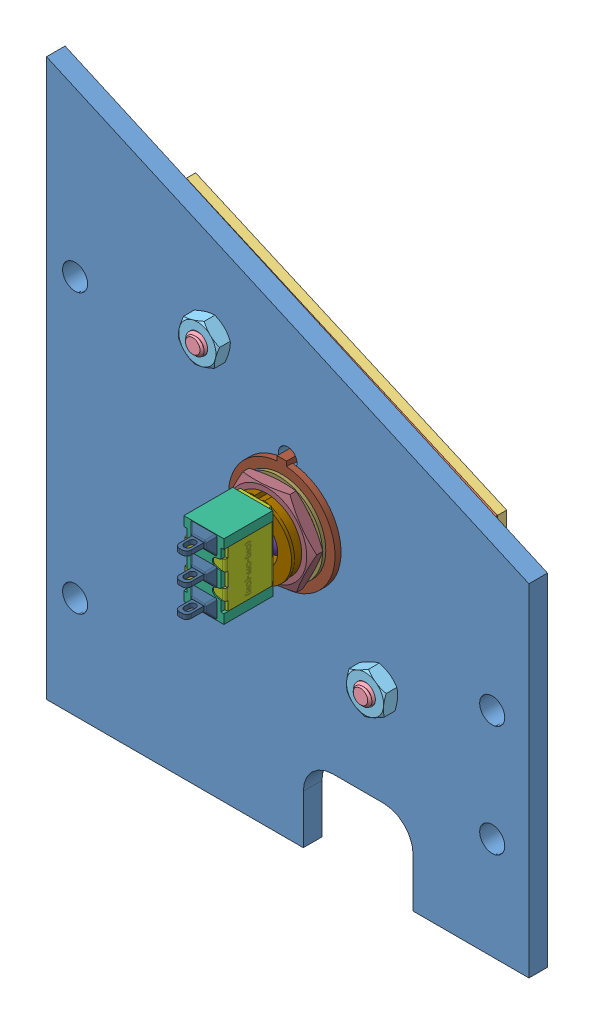
SolidWorks assembly FIRE TEST Panel, configuration Default. Lengths in mm.
Overall size (82.55 80.05 42.41).
17 component instances, 13 part files, 11 mates.
Components (placement in the parent):
- FIRE TEST Panel Backplate-1: FIRE TEST Panel Backplate [Default] at origin size (82.55 80.05 3.17)
- FIRE TEST Panel Lightplate-1: FIRE TEST Panel Lightplate [Default] at (0 0 -3.175) x (-1 0 0) z (0 0 -1) size (55.25 58.42 4.76)
- FIRE TEST Panel Legend Plate-1: FIRE TEST Panel Legend Plate [Default] at (0 0 -7.9375) x (-1 0 0) z (0 0 -1) size (55.25 58.42 1.59)
- 91249A148 - PHS, 6-32 X .500, 18-8, BLACK-OXIDE-1: 91249A148 - PHS, 6-32 X .500, 18-8, BLACK-OXIDE [91249A148] at (28.194 68.072 3.175) x (-0.99905 0.043571 0) z (0 0 -1) size (6.86 6.86 15.21)
- 90760A007 - NUT, 6-32, JAM, STEEL, ZINC-PLATED-1: 90760A007 - NUT, 6-32, JAM, STEEL, ZINC-PLATED [90760A007] at (28.194 68.072 1.1906) x (0.275217 -0.961382 0) z (-0.961382 -0.275217 0) size (6.35 2.99 7.33)
- 91249A148 - PHS, 6-32 X .500, 18-8, BLACK-OXIDE-2: 91249A148 - PHS, 6-32 X .500, 18-8, BLACK-OXIDE [91249A148] at (56.896 30.48 3.175) x (-0.993321 -0.115383 0) z (0 0 -1) size (6.86 6.86 15.21)
- 90760A007 - NUT, 6-32, JAM, STEEL, ZINC-PLATED-2: 90760A007 - NUT, 6-32, JAM, STEEL, ZINC-PLATED [90760A007] at (56.896 30.48 1.1906) x (0.424166 -0.905585 0) z (-0.905585 -0.424166 0) size (6.35 2.99 7.33)
- 100SPxT8B13M1QEH - SWITCH, TOGGLE, SPDT, 18mm BAT-1: 100SPxT8B13M1QEH - SWITCH, TOGGLE, SPDT, 18mm BAT [100SP4T8B13M1QEH] at (41.275 46.99 14.3538) x (0 1 0) z (0 0 -1) size (19 18.28 42.41)
  - 100-300SPXBODY-1: 100-300SPXBODY [Default] at origin size (12.7 6.86 8.38)
  - 100SPXBRACKET_1-1: 100SPXBRACKET_1 [100SP4T8B13M1QEH] at (0 0 0.19) size (12.7 6.86 8.7)
  - 100T8-1: 100T8 [Default] at (0 0 13.35) x (-0.976296 0 -0.21644) z (-0.21644 0 0.976296) size (7.5 7.5 28.63)
  - 100B13BUSHING-1: 100B13BUSHING [Default] at (0 0 0.51) x (-1 0 0) z (0 0 1) size (12.18 12.24 11.89)
  - 100-300SPXM1-1: 100-300SPXM1 [Default] x (-1 0 0) z (0 0 -1) size (12.56 4.43 3.96)
  - HDW17 - LOCKING RING, B13-1: HDW17 - LOCKING RING, B13 [Default] at (0 0 13.3378) x (0 1 0) z (1 0 0) size (18.24 3.3 19)
  - HDW12 - LOCK WASHER, B13-1: HDW12 - LOCK WASHER, B13 [Default] at (0 0 12.779) x (1 0 0) z (0 -1 0) size (15.06 0.56 15.06)
  - HDW4 - NUT, B13-1: HDW4 - NUT, B13 [Default] at (0 0 10.7978) x (0.996778 -0.080205 0) z (-0.080205 -0.996778 0) size (14 1.98 16.16)
  - HDW4 - NUT, B13-2: HDW4 - NUT, B13 [Default] at (0 0 17.5288) x (0.98588 -0.167452 0) z (-0.167452 -0.98588 0) size (14 1.98 16.16)
Mates (geometry in assembly coordinates):
- Concentric1: concentric anti-aligned: cylinder of FIRE TEST Panel Legend Plate-1 through (28.194 68.072 -9.525) axis (0 0 -1) radius 2.1526; cylinder of 91249A148 - PHS, 6-32 X .500, 18-8, BLACK-OXIDE-1 through (28.194 68.072 3.175) axis (0 0 1) radius 3.429
- Concentric2: concentric aligned: cylinder of 91249A148 - PHS, 6-32 X .500, 18-8, BLACK-OXIDE-1 through (28.194 68.072 3.175) axis (0 0 1) radius 3.429; circle of 90760A007 - NUT, 6-32, JAM, STEEL, ZINC-PLATED-1
- Coincident1: coincident anti-aligned: plane of FIRE TEST Panel Backplate-1 through (49.022 8.382 0) normal (0 0 1); plane of 90760A007 - NUT, 6-32, JAM, STEEL, ZINC-PLATED-1 through (29.0825 71.6289 0) normal (0 0 -1)
- Coincident2: coincident anti-aligned: plane of FIRE TEST Panel Legend Plate-1 through (9.652 65.0875 -9.525) normal (0 0 -1); plane of 91249A148 - PHS, 6-32 X .500, 18-8, BLACK-OXIDE-1 through (28.194 68.072 -9.525) normal (0 0 1)
- Concentric3: concentric aligned: cylinder of 91249A148 - PHS, 6-32 X .500, 18-8, BLACK-OXIDE-2 through (56.896 30.48 3.175) axis (0 0 1) radius 3.429; circle of 90760A007 - NUT, 6-32, JAM, STEEL, ZINC-PLATED-2
- Coincident3: coincident anti-aligned: plane of FIRE TEST Panel Backplate-1 through (49.022 8.382 0) normal (0 0 1); plane of 90760A007 - NUT, 6-32, JAM, STEEL, ZINC-PLATED-2 through (57.2093 34.1328 0) normal (0 0 -1)
- Coincident4: coincident anti-aligned: plane of FIRE TEST Panel Legend Plate-1 through (9.652 65.0875 -9.525) normal (0 0 -1); plane of 91249A148 - PHS, 6-32 X .500, 18-8, BLACK-OXIDE-2 through (56.896 30.48 -9.525) normal (0 0 1)
- Concentric4: concentric anti-aligned: cylinder of FIRE TEST Panel Legend Plate-1 through (56.896 30.48 -9.525) axis (0 0 -1) radius 2.1526; cylinder of 91249A148 - PHS, 6-32 X .500, 18-8, BLACK-OXIDE-2 through (56.896 30.48 3.175) axis (0 0 1) radius 3.429
- Concentric5: concentric aligned: cylinder of FIRE TEST Panel Backplate-1 through (41.275 46.99 -3.175) axis (0 0 -1) radius 6.35; cylinder of 100SPxT8B13M1QEH - SWITCH, TOGGLE, SPDT, 18mm BAT-1/100B13BUSHING-1 through (41.275 46.99 4.9538) axis (0 0 -1) radius 5.925
- Coincident5: coincident anti-aligned: plane of FIRE TEST Panel Backplate-1 through (49.022 8.382 0) normal (0 0 1); plane of 100SPxT8B13M1QEH - SWITCH, TOGGLE, SPDT, 18mm BAT-1/HDW17 - LOCKING RING, B13-1 through (41.275 46.99 0) normal (0 0 -1)
- Parallel1: parallel aligned: plane of FIRE TEST Panel Backplate-1 through (0 95.25 -3.175) normal (-1 0 0); plane of 100SPxT8B13M1QEH - SWITCH, TOGGLE, SPDT, 18mm BAT-1/100SPXBRACKET_1-1 through (37.845 46.99 6.2238) normal (-1 0 0)
